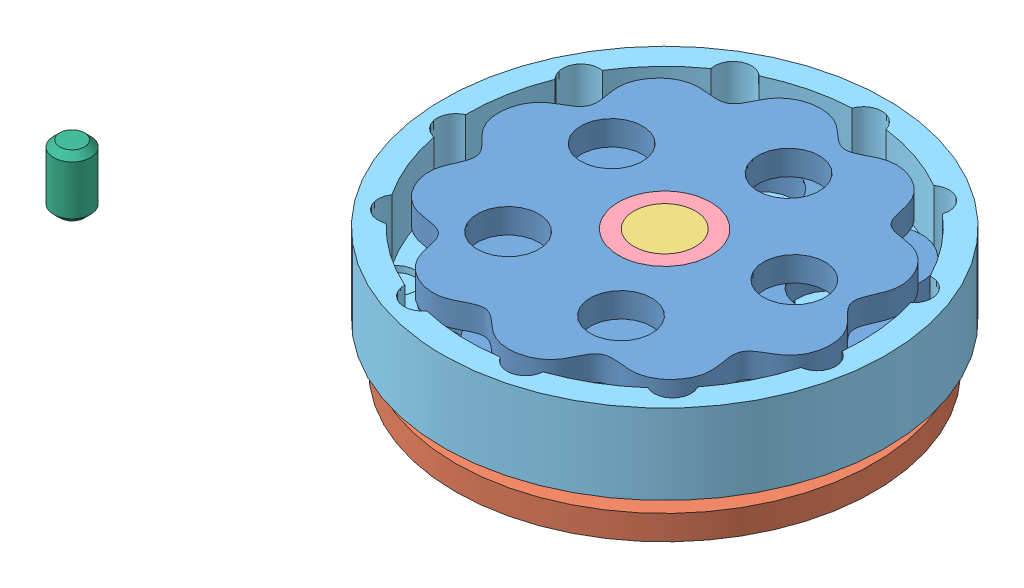
SolidWorks assembly 减速器, configuration 默认. Lengths in mm.
Overall size (87.24 39.97 100.23).
8 component instances, 6 part files, 15 mates.
Components (placement in the parent):
- 摆线盘-1: 摆线盘 [默认] at (0.5133 12 -1.3378) x (0.743371 0 0.668879) z (0 1 0) size (57.81 60.03 4)
- 电机转接盘-1: 电机转接盘 [默认] at origin size (68 9 68)
- 偏心轴-1: 偏心轴 [默认] at (0 6 0) x (-1 0 0) z (0 0 -1) size (12 14 10)
- 轴承-1: 轴承 [10-15-4] at (2 12 0) size (15 4 15)
- 减速器上座-1: 减速器上座 [默认] at (0 10.2281 0) x (0.999118 0 0.041985) z (-0.041985 0 0.999118) size (72 13 72)
- 销-1: 销 [D6H10] at (-40.6732 29.9699 55.5836) size (6 10 6)
- 摆线盘-2: 摆线盘 [默认] at (-1.9646 16 0.3745) x (0.982316 0 -0.18723) z (0 1 0) size (57.81 60.03 4)
- 轴承-2: 轴承 [10-15-4] at (0 16 0) size (15 4 15)
Mates (geometry in assembly coordinates):
- 同心1: concentric: cylinder of assembly; cylinder of assembly; cylinder of 电机转接盘-1 through (0 6 0) axis (0 -1 0) radius 5; cylinder of 偏心轴-1 through (0 12 0) axis (0 -1 0) radius 5
- 重合1: coincident: plane of assembly; plane of assembly; plane of 电机转接盘-1 through (-4.3301 9 2.5) normal (0 0 1); plane of 偏心轴-1 through (4.3301 9 2.5) normal (0 0 -1)
- 重合2: coincident: plane of assembly; plane of assembly; plane of 电机转接盘-1 through (0 9 0) normal (0 1 0); plane of 偏心轴-1 through (0 9 0) normal (0 -1 0)
- 重合3: coincident: plane of assembly through (0 0 0) normal (0 0 1); plane of 电机转接盘-1 through (0 0 0) normal (0 0 1); plane of assembly
- 重合4: coincident: plane of assembly through (0 0 0) normal (0 1 0); plane of 电机转接盘-1 through (0 0 0) normal (0 1 0); plane of assembly
- 重合5: coincident: plane of assembly through (0 0 0) normal (1 0 0); plane of 电机转接盘-1 through (0 0 0) normal (1 0 0); plane of assembly
- 同心2: concentric: cylinder of assembly; cylinder of assembly; cylinder of 偏心轴-1 through (2 16 0) axis (0 -1 0) radius 5; cylinder of 轴承-1 through (2 16 0) axis (0 -1 0) radius 5
- 重合6: coincident: plane of assembly; plane of assembly; plane of 偏心轴-1 through (2 16 0) normal (0 1 0); plane of 轴承-1 through (2 16 0) normal (0 1 0)
- 同心3: concentric: cylinder of assembly; cylinder of assembly; cylinder of 偏心轴-1 through (0 20 0) axis (0 -1 0) radius 5; cylinder of 轴承-2 through (0 20 0) axis (0 -1 0) radius 5
- 重合7: coincident: plane of assembly; plane of assembly; plane of 偏心轴-1 through (0 20 0) normal (0 1 0); plane of 轴承-2 through (0 20 0) normal (0 1 0)
- 同心4: concentric: cylinder of assembly; cylinder of assembly; cylinder of 摆线盘-1 through (2 12 0) axis (0 1 0) radius 7.5; cylinder of 轴承-1 through (2 16 0) axis (0 -1 0) radius 7.5
- 同心5: concentric: cylinder of assembly; cylinder of assembly; cylinder of 摆线盘-2 through (0 16 0) axis (0 1 0) radius 7.5; cylinder of 轴承-2 through (0 20 0) axis (0 -1 0) radius 7.5
- 重合8: coincident: plane of assembly; plane of assembly; plane of 摆线盘-2 through (0 20 0) normal (0 1 0); plane of 轴承-2 through (0 20 0) normal (0 1 0)
- 重合9: coincident: plane of assembly; plane of assembly; plane of 摆线盘-1 through (2 16 0) normal (0 1 0); plane of 轴承-1 through (2 16 0) normal (0 1 0)
- 同心6: concentric: cylinder of assembly; cylinder of assembly; cylinder of 电机转接盘-1 through (0 4 0) axis (0 -1 0) radius 34; cylinder of 减速器上座-1 through (0 20.2281 0) axis (0 -1 0) radius 36
